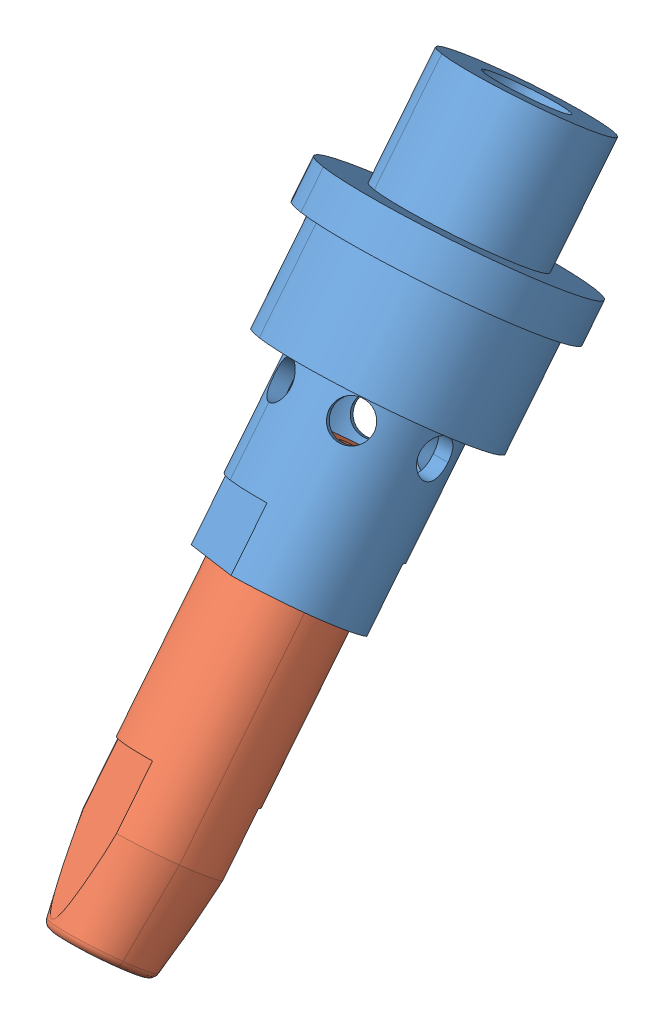
SolidWorks assembly lapmohan1, configuration Default. Lengths in mm.
Overall size (5.81 13.11 11.42).
9 component instances, 8 part files, 0 mates.
Components (placement in the parent):
- lapmohan1.STEP-1: lapmohan1.STEP [Default] at origin size (5.81 13.11 11.42)
  - 3.STEP-1: 3.STEP [Default] at (-7.1454 -70.2127 -64.5307) (suppressed, hidden)
  - 14.STEP-1: 14.STEP [Default] at (-9.7774 -85.1837 -97.594) x (0.999909 -0.013434 -0.001461) z (0.001461 -0.00001 0.999999) (suppressed, hidden)
  - 15.STEP-1: 15.STEP [Default] at (-13.7833 -97.0041 -10.9661) x (0.999027 -0.043837 -0.004766) z (0.004766 -0.000105 0.999989) (suppressed, hidden)
  - 16.STEP-1: 16.STEP [Default] at (-34.2956 -34.3708 -252.4685) x (0.995812 -0.064412 -0.064876) z (0.064901 -0.001705 0.99789) size (4.81 8.31 7.51)
  - 17.STEP-1: 17.STEP [Default] at (-97.5509 -12.3785 -249.9919) x (0.953178 -0.196823 -0.229593) z (0.229874 -0.021732 0.972978) size (2.61 7.67 6.72)
  - 18.STEP-1: 18.STEP [Default] at (299.1418 213.1741 30.1211) x (-0.293384 0.591486 0.751046) z (-0.743309 -0.635174 0.20987) (suppressed, hidden)
  - 1.STEP-1: 1.STEP [Default] at (-14.2523 -28.7683 -49.0627) (suppressed, hidden)
  - lock.STEP-1: lock.STEP [Default] at (-21.303 -3.5795 92.1778) x (1 0 0) z (0 0.753025 -0.657991) (suppressed, hidden)
